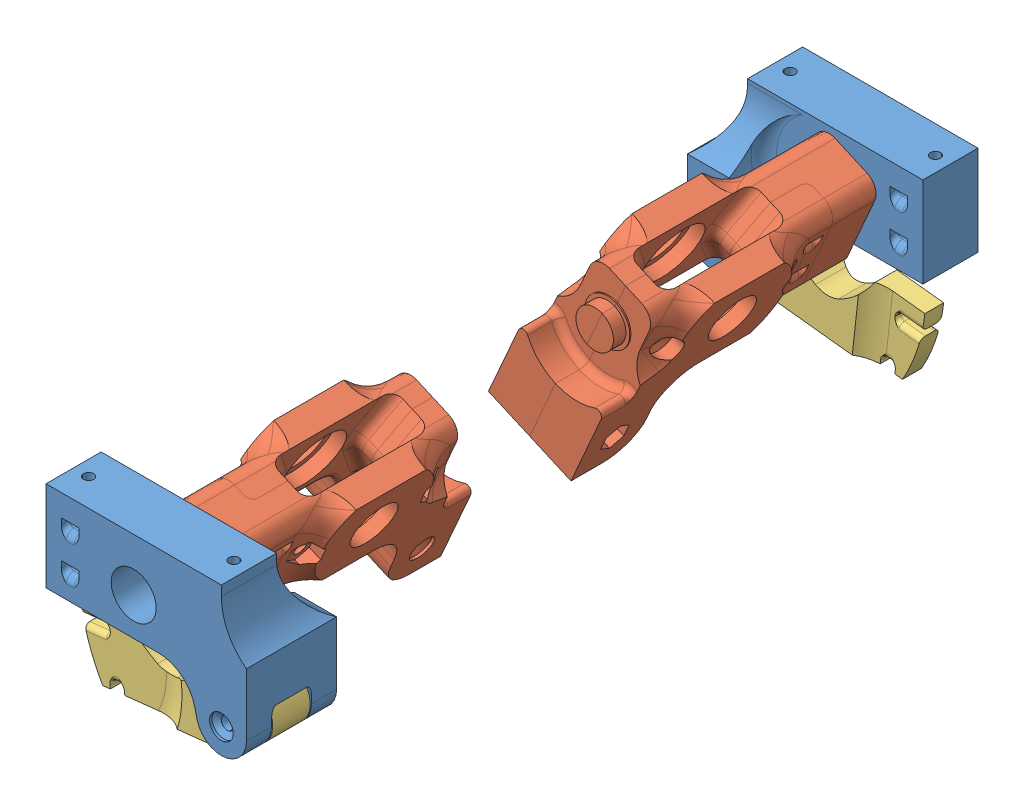
SolidWorks assembly Yaw Assembly, configuration Default. Lengths in mm.
Overall size (93.63 76.13 302).
8 component instances, 4 part files, 20 mates.
Components (placement in the parent):
- Bearing Block B-1: Bearing Block B [Default] at origin size (81.49 59 37.49)
- Axis B Block-1: Axis B Block [Default] at (0 -3 61.5) x (0 0 -1) z (0.915337 -0.402688 0) size (108 64.09 38.74)
- CAM Yaw-1: CAM Yaw [Default] at (-35 -31 -2.75) x (-0.993874 0.110515 0) z (0 0 -1) size (80 28 17.41)
- Bearing-1: Bearing [685] at (-10.0672 -25.8834 1.5) x (0 0 -1) z (1 0 0) size (5 11 11)
- Axis B Block-2: Axis B Block [Default] at (0 -3 204.5) x (0 0 1) z (-0.915337 0.402688 0) size (108 64.09 38.74)
- Bearing Block B-2: Bearing Block B [Default] at (0 0 266) x (-1 0 0) z (0 0 -1) size (81.49 59 37.49)
- CAM Yaw-2: CAM Yaw [Default] at (35 -31 268.75) x (0.993931 0.110001 0) z (0 0 1) size (80 28 17.41)
- Bearing-2: Bearing [685] at (-10.0672 -25.8834 264.5) x (0 0 1) z (-0.851773 -0.523912 0) size (5 11 11)
Mates (geometry in assembly coordinates):
- Coincident1: coordinate: point of Bearing Block B-1
- Concentric1: concentric anti-aligned: cylinder of Bearing Block B-1 through (0 -3 18) axis (0 0 -1) radius 9; cylinder of Axis B Block-1 through (0 -3 61.5) axis (0 0 1) radius 7.5
- Coincident2: coincident anti-aligned: plane of Bearing Block B-1 through (0 -3 4) normal (0 0 1); plane of Axis B Block-1 through (3.0202 3.865 4) normal (0 0 -1)
- Concentric2: concentric anti-aligned: cylinder of Bearing Block B-1 through (-35 -31 18) axis (0 0 -1) radius 2.5; cylinder of CAM Yaw-1 through (-35 -31 -17.75) axis (0 0 1) radius 3
- Coincident3: coincident anti-aligned: plane of Bearing Block B-1 through (-35 -31 -7.5) normal (0 0 1); plane of CAM Yaw-1 through (-35 -31 -7.5) normal (0 0 -1)
- Concentric3: concentric anti-aligned: cylinder of Axis B Block-1 through (-10.0672 -25.8834 26.5) axis (0 0 -1) radius 2.25; cylinder of Bearing-1 through (-10.0672 -25.8834 11.0787) axis (0 0 1) radius 2.5
- Coincident4: coincident anti-aligned: plane of Axis B Block-1 through (-10.0672 -25.8834 4) normal (0 0 -1); plane of Bearing-1 through (-10.0672 -21.9834 4) normal (0 0 1)
- PathMate1: path: point of Bearing-1; curve of CAM Yaw-1
- Coincident6: coincident aligned: plane of Bearing Block B-1 through (35 18 18) normal (0 1 0); plane of Bearing Block B-2 through (-35 18 248) normal (0 1 0)
- Concentric4: concentric anti-aligned: cylinder of Bearing Block B-1 through (0 -3 18) axis (0 0 -1) radius 9; cylinder of Bearing Block B-2 through (0 -3 248) axis (0 0 1) radius 9
- Concentric6: concentric anti-aligned: cylinder of Axis B Block-2 through (0 -3 204.5) axis (0 0 -1) radius 7.5; cylinder of Bearing Block B-2 through (0 -3 248) axis (0 0 1) radius 9
- Coincident7: coincident anti-aligned: plane of Axis B Block-2 through (3.0202 3.865 262) normal (0 0 1); plane of Bearing Block B-2 through (0 -3 262) normal (0 0 -1)
- Concentric7: concentric anti-aligned: cylinder of Bearing Block B-2 through (35 -31 248) axis (0 0 1) radius 2.5; cylinder of CAM Yaw-2 through (35 -31 283.75) axis (0 0 -1) radius 3
- Coincident8: coincident anti-aligned: plane of Bearing Block B-2 through (35 -31 273.5) normal (0 0 -1); plane of CAM Yaw-2 through (35 -31 273.5) normal (0 0 1)
- Distance1: distance = 280 mm aligned: plane of Bearing Block B-2 through (35 -31 284) normal (0 0 1); plane of Bearing Block B-1 through (0 -3 4) normal (0 0 1)
- Concentric8: concentric anti-aligned: cylinder of Axis B Block-2 through (-10.0672 -25.8834 239.5) axis (0 0 1) radius 2.25; cylinder of Bearing-2 through (-10.0672 -25.8834 254.9213) axis (0 0 -1) radius 2.5
- Coincident10: coincident anti-aligned: plane of Axis B Block-2 through (-10.0672 -25.8834 262) normal (0 0 1); plane of Bearing-2 through (-12.1104 -22.5615 262) normal (0 0 -1)
- PathMate2: path: unknown of Bearing-2; edge_curve of CAM Yaw-2
- Parallel1: parallel anti-aligned: plane of Axis B Block-1 through (0 -3 61.5) normal (0.915337 -0.402688 0); plane of Axis B Block-2 through (0 -3 204.5) normal (-0.915337 0.402688 0)
- LimitAngle1: limit planar angle = 0.414451 rad aligned: plane of Axis B Block-1 through (0 -3 61.5) normal (0.915337 -0.402688 0)
